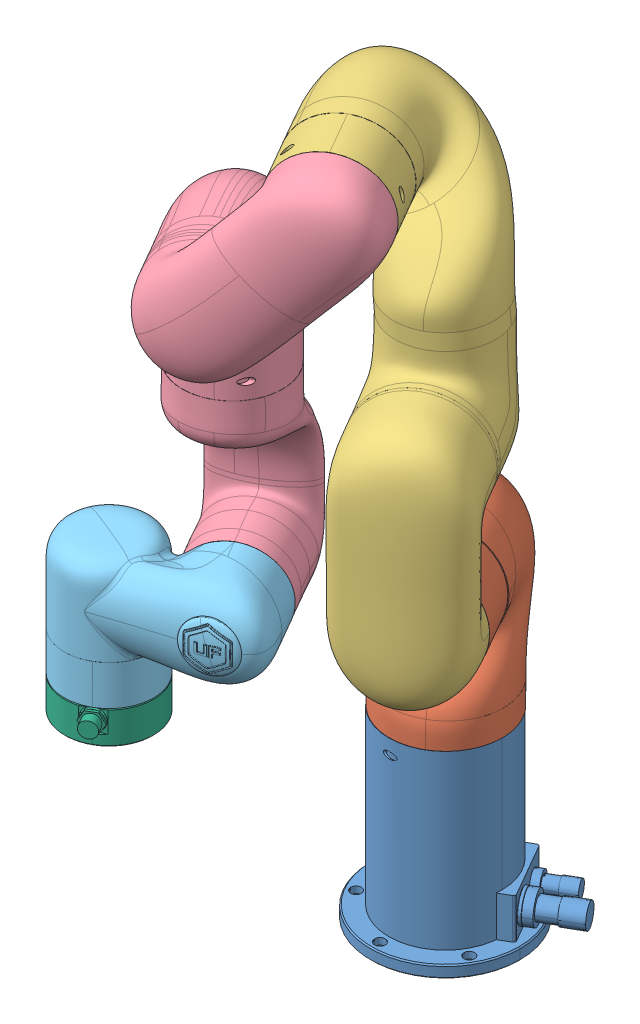
SolidWorks assembly xArm5(XF1300), configuration Default. Lengths in mm.
Overall size (331.48 594.68 264.08).
7 component instances, 6 part files, 0 mates.
Components (placement in the parent):
- xArm5(XF1300).STEP-1: xArm5(XF1300).STEP [Default] at origin size (331.48 594.68 264.08)
  - J1.STEP-1: J1.STEP [Default] at (-532.9645 8.759 -232.0025) size (153.99 154.8 126)
  - J2.STEP-1: J2.STEP [Default] at (-538.6068 215.9039 -238.1379) x (0.866025 0 -0.5) z (0 1 0) size (97.39 133.17 171.15)
  - J3.STEP-1: J3.STEP [Default] at (-538.8934 390.4025 -198.9217) x (0.5 0 0.866025) z (0 -1 0) size (188.25 143.36 375.02)
  - J4.STEP-1: J4.STEP [Default] at (-591.9586 475.9658 -159.5395) x (-0.866025 0.000472 0.5) z (-0.5 0 -0.866025) size (163.29 422.1 193.94)
  - J5.STEP-1: J5.STEP [Default] at (-668.9511 191.4192 -141.7491) x (0.866025 0 -0.5) z (0 1 0) size (151.08 96.1 106.05)
  - Tool head.STEP-1: Tool head.STEP [Default] at (-713.4197 36.4095 -146.714) x (-0.5 0 -0.866025) z (0 1 0) size (85.9 75 28.5)
